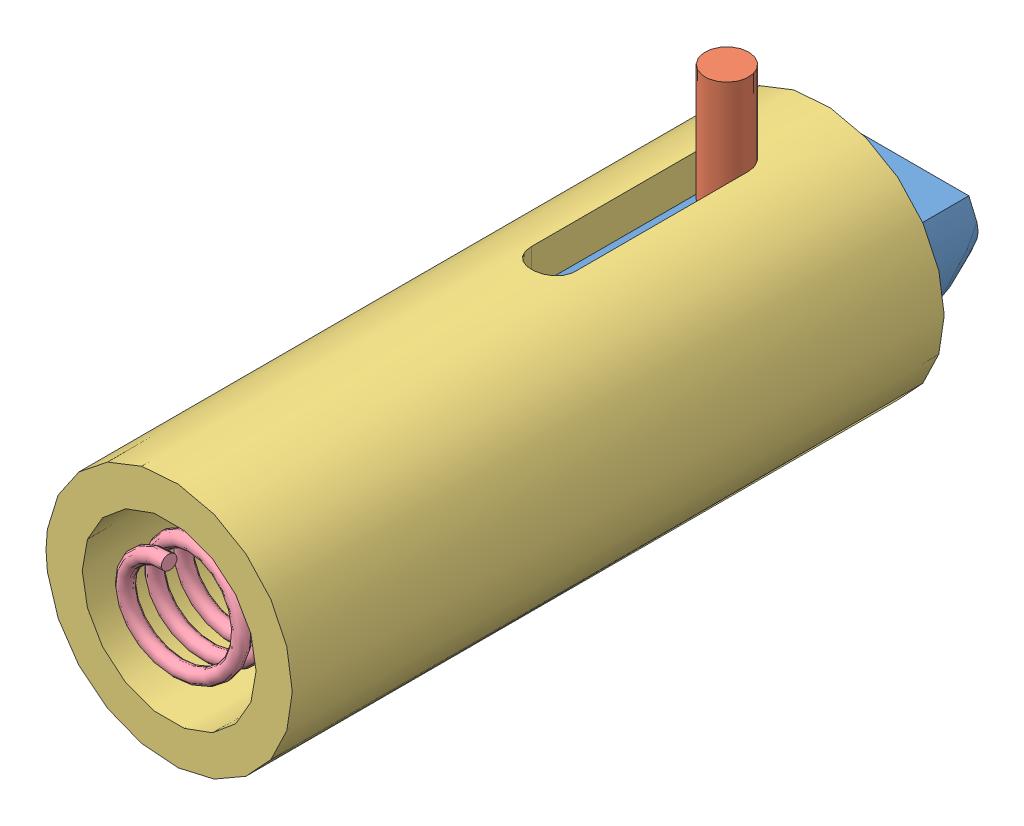
SolidWorks assembly Assem5, configuration Default. Lengths in mm.
Overall size (17 22.5 50.5).
4 component instances, 4 part files, 7 mates.
Components (placement in the parent):
- Part612-1: Part612 [Default] at (4.1987 6.9304 -6.924) size (12 12 30)
- Part123-1: Part123 [Default] at (4.1987 9.9304 4.576) size (3 11 3)
- Part521-1: Part521 [Default] at (4.1987 6.9304 43.076) x (-1 0 0) z (0 0 -1) size (17 17 45)
- Part9213-1: Part9213 [Default] at (4.1987 6.9304 43.076) x (1 0 0) z (0 1 0) size (9.46 33 9.03)
Mates (geometry in assembly coordinates):
- Concentric1: concentric anti-aligned: cylinder of Part612-1 through (4.1987 6.9304 11.076) axis (0 0 1) radius 4; circle of Part9213-1
- Coincident1: coincident anti-aligned: plane of Part612-1 through (4.1987 6.9304 11.076) normal (0 0 1); circle of Part9213-1
- Concentric2: concentric anti-aligned: cylinder of Part612-1 through (4.1987 6.9304 23.076) axis (0 0 -1) radius 6; cylinder of Part521-1 through (4.1987 6.9304 -1.924) axis (0 0 1) radius 6
- Concentric3: concentric anti-aligned: cylinder of Part612-1 through (4.1987 9.9304 4.576) axis (0 1 0) radius 1.5; cylinder of Part123-1 through (4.1987 20.9304 4.576) axis (0 -1 0) radius 1.5
- Coincident2: coincident anti-aligned: plane of Part612-1 through (4.1987 9.9304 4.576) normal (0 1 0); plane of Part123-1 through (4.1987 9.9304 4.576) normal (0 -1 0)
- Tangent1: tangent anti-aligned: cylinder of Part123-1 through (4.1987 20.9304 4.576) axis (0 -1 0) radius 1.5; plane of Part521-1 through (2.6987 -1.5706 4.576) normal (1 0 0)
- Concentric4: concentric anti-aligned: cylinder of Part123-1 through (4.1987 20.9304 4.576) axis (0 -1 0) radius 1.5; cylinder of Part521-1 through (4.1987 -1.5706 4.576) axis (0 1 0) radius 1.5
